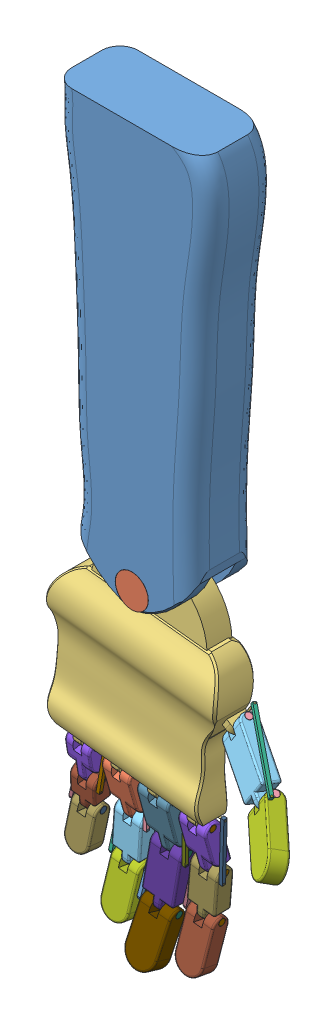
SolidWorks assembly Hand, configuration Default. Lengths in mm.
Overall size (1770.06 4643.82 693.31).
40 component instances, 31 part files, 90 mates.
Components (placement in the parent):
- arm2-2: arm2 [Default] at (66.057 -996.4106 3559.1648) x (-1 0 0) z (0 1 0) size (1268.57 632.71 2564.87)
- armpin2-1: armpin2 [Default] at (66.057 -1176.4106 3359.1648) size (200 200 400)
- palm2-1: palm2 [Default] at (-49.7867 -1857.8333 3453.0614) x (-0.994014 0.109254 0) z (0.109254 0.994014 0) size (1069.09 253.19 1333.97)
- Whitepinthumb2-1: Whitepinthumb2 [Default] at (444.8112 -1862.5283 3540.0476) x (0.743563 -0.485544 -0.45974) z (0.546751 0.837295 0) size (40 40 200)
- bottomthumb2-1: bottomthumb2 [Default] at (602.4673 -1846.045 3639.4098) x (-0.546751 -0.837295 0) z (-0.293211 0.191466 0.936679) size (202.17 424 100.1)
- llink2palmThumb-1: llink2palmThumb [Default] at (692.7586 -1782.9453 3602.1353) x (0.417114 -0.272374 -0.867081) z (0.726003 -0.474077 0.498168) size (20 20 462)
- topThumb2-1: topThumb2 [Default] at (853.3079 -2009.6042 3786.5629) x (-0.546751 -0.837295 0) z (-0.500891 0.32708 0.801328) size (223.09 400 100.1)
- Whitepinthumb2-2: Whitepinthumb2 [Default] at (849.1589 -1887.4628 3671.7184) x (0.743563 -0.485544 0.45974) z (-0.546751 -0.837295 0) size (40 40 200)
- bottomIndex2-1: bottomIndex2 [Default] at (237.9873 -2518.7706 3544.9319) x (-0.994014 0.109254 0) z (-0.036869 -0.335441 0.941339) size (192.89 374 100.1)
- WhitepinIndex-1: WhitepinIndex [Default] at (337.1775 -2394.3221 3540.0476) x (0.00717 0.065231 0.997844) z (-0.994014 0.109254 0) size (40 40 170)
- link1palm-1: link1palm [Default] at (342.7622 -2546.7081 3474.8213) x (0.009115 0.082932 -0.996514) z (0.108873 0.990548 0.083431) size (20 20 387)
- topIndex2-1: topIndex2 [Default] at (179.7632 -3052.1677 3490.7878) x (-0.994014 0.109254 0) z (0.021291 0.193713 0.980827) size (193.09 335 100.1)
- upIndex2-1: upIndex2 [Default] at (208.2828 -2790.8593 3477.1977) x (-0.994014 0.109254 0) z (-0.003078 -0.028007 0.999603) size (193.09 324 100.1)
- WhitepinIndex-2: WhitepinIndex [Default] at (303.8489 -2699.3835 3430.0351) x (0.005058 0.046018 0.998928) z (-0.994014 0.109254 0) size (40 40 170)
- WhitepinIndex-3: WhitepinIndex [Default] at (273.9057 -2973.6443 3422.2586) x (0.012952 0.117841 0.992948) z (-0.994014 0.109254 0) size (40 40 170)
- link2-1: link2 [Default] at (101.6614 -2964.6124 3449.7024) x (0.049922 0.454198 -0.889501) z (0.097181 0.884176 0.456933) size (202.48 20 293.97)
- bottomMiddle2-1: bottomMiddle2 [Default] at (-3.1499 -2515.9675 3537.8989) x (-0.994014 0.109254 0) z (-0.035954 -0.327121 0.944298) size (202.89 424 100.1)
- Whitepinmiddle2-1: Whitepinmiddle2 [Default] at (108.5543 -2369.1937 3540.0476) x (0.054133 0.492512 0.86862) z (-0.994014 0.109254 0) size (40 40 190)
- llinkMiddle-1: llinkMiddle [Default] at (111.2099 -2548.2299 3469.536) x (0.010688 0.097237 -0.995204) z (0.10873 0.989246 0.097823) size (20 20 434)
- upMiddle2-1: upMiddle2 [Default] at (-37.6689 -2831.8595 3475.7117) x (-0.994014 0.109254 0) z (0.008345 0.075929 0.997078) size (213.09 374 100.1)
- topMiddle2-1: topMiddle2 [Default] at (-68.5218 -3114.3963 3519.33) x (-0.994014 0.109254 0) z (0.033324 0.303187 0.952348) size (213.09 345 100.1)
- Whitepinmiddle2-2: Whitepinmiddle2 [Default] at (34.6481 -3045.27 3441.2114) x (0.051008 0.464078 0.884324) z (-0.994014 0.109254 0) size (40 40 190)
- Whitepinmiddle2-3: Whitepinmiddle2 [Default] at (69.962 -2722.1463 3416.3095) x (0.05381 0.489577 0.870298) z (-0.994014 0.109254 0) size (40 40 190)
- linkmid2-1: linkmid2 [Default] at (-115.8972 -2657.5866 3399.8278) x (-0.042435 -0.386079 0.921489) z (-0.100676 -0.915973 -0.388404) size (236.96 20 342.7)
- bottomRing2-1: bottomRing2 [Default] at (-222.8909 -2468.1442 3544.0434) x (-0.994014 0.109254 0) z (-0.037547 -0.341612 0.939091) size (192.89 374 100.1)
- WhitepinRing-1: WhitepinRing [Default] at (-123.6974 -2343.6665 3540.0476) x (0.017517 0.159372 0.987063) z (-0.994014 0.109254 0) size (40 40 170)
- llink2palmRing-1: llink2palmRing [Default] at (-118.2995 -2495.9208 3473.5529) x (0.009875 0.089841 -0.995907) z (0.108807 0.989946 0.090382) size (20 20 387)
- upRing2-1: upRing2 [Default] at (-252.6012 -2740.2855 3473.3803) x (-0.994014 0.109254 0) z (-0.005002 -0.045511 0.998951) size (193.09 324 100.1)
- WhitepinRing-2: WhitepinRing [Default] at (-156.9459 -2647.9993 3428.0113) x (0.04458 0.405596 0.912965) z (-0.994014 0.109254 0) size (40 40 170)
- WhitepinRing-3: WhitepinRing [Default] at (-187.2671 -2922.0376 3415.3746) x (0.042318 0.38502 0.921938) z (-0.994014 0.109254 0) size (40 40 170)
- linkRing2-1: linkRing2 [Default] at (-323.2952 -2585.3326 3412.2107) x (-0.051499 -0.468548 0.881936) z (-0.096355 -0.876656 -0.47137) size (202.48 20 293.97)
- topRing2-1: topRing2 [Default] at (-281.5753 -3002.068 3481.9035) x (-0.994014 0.109254 0) z (0.01888 0.171778 0.984955) size (193.09 335 100.1)
- bottomlittle2-1: bottomlittle2 [Default] at (-446.0836 -2393.6088 3570.4269) x (-0.994014 0.109254 0) z (-0.02642 -0.240374 0.970321) size (172.89 274 100.1)
- linklittle-1: linklittle [Default] at (-372.4692 -2428.6302 3500.2685) x (-0.007809 -0.071048 -0.997442) z (-0.108974 -0.991472 0.071475) size (20 20 298)
- Whitepinlittle2-1: Whitepinlittle2 [Default] at (-386.4181 -2535.4036 3485.3958) x (-0.080786 -0.735011 0.673225) z (-0.994014 0.109254 0) size (40 40 150)
- Whitepinlittle2-2: Whitepinlittle2 [Default] at (-362.2608 -2317.4457 3540.0476) x (-0.101503 -0.923497 0.369933) z (-0.994014 0.109254 0) size (40 40 150)
- uplittle2-1: uplittle2 [Default] at (-467.2053 -2583.9477 3527.1317) x (-0.994014 0.109254 0) z (-0.016764 -0.152521 0.988158) size (173.09 224 100.1)
- toplittle2-1: toplittle2 [Default] at (-487.6102 -2767.7651 3517.4326) x (-0.994014 0.109254 0) z (0.013751 0.12511 0.992048) size (173.09 275 100.1)
- linklittle2-1: linklittle2 [Default] at (-532.5016 -2476.907 3464.9918) x (-0.051863 -0.471861 0.880146) z (-0.096159 -0.874877 -0.474703) size (144.28 20 209.86)
- Whitepinlittle2-3: Whitepinlittle2 [Default] at (-405.6178 -2708.2564 3458.3905) x (-0.080781 -0.734964 0.673278) z (-0.994014 0.109254 0) size (40 40 150)
Mates (geometry in assembly coordinates):
- Concentric1: concentric: cylinder of arm2-2 through (66.057 -1176.4106 3359.1648) axis (0 0 1) radius 100; cylinder of armpin2-1 through (66.057 -1176.4106 3759.1648) axis (0 0 -1) radius 100
- Coincident1: coincident: plane of arm2-2 through (66.057 -996.4106 3759.1648) normal (0 0 1); plane of armpin2-1 through (66.057 -1176.4106 3759.1648) normal (0 0 1)
- Concentric2: concentric: cylinder of armpin2-1 through (66.057 -1176.4106 3759.1648) axis (0 0 -1) radius 100; cylinder of palm2-1 through (66.057 -1176.4106 3445.0448) axis (0 0 1) radius 100
- Coincident3: coincident: plane of arm2-2 through (416.057 -996.4106 3634.6648) normal (0 0 -1); plane of palm2-1 through (428.1649 -1085.4276 3634.6648) normal (0 0 1)
- Concentric3: concentric: cylinder of palm2-1 through (472.6955 -1819.8263 3540.0476) axis (0.546751 0.837295 0) radius 20; cylinder of Whitepinthumb2-1 through (554.1614 -1695.0693 3540.0476) axis (-0.546751 -0.837295 0) radius 20
- Concentric4: concentric: cylinder of Whitepinthumb2-1 through (554.1614 -1695.0693 3540.0476) axis (-0.546751 -0.837295 0) radius 20; cylinder of bottomthumb2-1 through (444.8112 -1862.5283 3540.0476) axis (0.546751 0.837295 0) radius 20
- Coincident4: coincident: plane of palm2-1; plane of bottomthumb2-1
- Coincident5: coincident: plane of Whitepinthumb2-1 through (554.1614 -1695.0693 3540.0476) normal (0.546751 0.837295 0); plane of bottomthumb2-1 through (823.712 -1871.0849 3607.0248) normal (0.546751 0.837295 0)
- Concentric5: concentric: cylinder of bottomthumb2-1 through (849.6436 -1886.7206 3671.7184) axis (-0.546751 -0.837295 0) radius 20; cylinder of Whitepinthumb2-2 through (739.8087 -2054.9218 3671.7184) axis (0.546751 0.837295 0) radius 20
- Concentric6: concentric: cylinder of topThumb2-1 through (739.8087 -2054.9218 3671.7184) axis (0.546751 0.837295 0) radius 20; cylinder of Whitepinthumb2-2 through (739.8087 -2054.9218 3671.7184) axis (0.546751 0.837295 0) radius 20
- Coincident6: coincident: plane of bottomthumb2-1 through (755.4775 -1975.5793 3607.0248) normal (-0.546751 -0.837295 0); plane of topThumb2-1 through (772.3122 -1986.5723 3601.7407) normal (0.546751 0.837295 0)
- Coincident7: coincident: plane of topThumb2-1 through (1058.7143 -2024.3017 3796.1637) normal (0.546751 0.837295 0); plane of Whitepinthumb2-2 through (849.1589 -1887.4628 3671.7184) normal (0.546751 0.837295 0)
- Concentric7: concentric: cylinder of llink2palmThumb-1 through (855.3542 -1889.1196 3713.705) axis (0.546751 0.837295 0) radius 5.75; cylinder of topThumb2-1 through (866.2892 -1872.3737 3713.705) axis (-0.546751 -0.837295 0) radius 5.75
- Concentric8: concentric: cylinder of palm2-1 through (539.1402 -1661.3741 3490.0476) axis (-0.546751 -0.837295 0) radius 5.75; cylinder of llink2palmThumb-1 through (529.4081 -1676.2779 3490.0476) axis (0.546751 0.837295 0) radius 5.75
- Coincident8: coincident: plane of llink2palmThumb-1 through (703.6936 -1766.1994 3602.1353) normal (0.546751 0.837295 0); plane of topThumb2-1 through (866.2892 -1872.3737 3713.705) normal (0.546751 0.837295 0)
- Concentric9: concentric: cylinder of palm2-1 through (478.9859 -2409.9085 3540.0476) axis (-0.994014 0.109254 0) radius 20; cylinder of WhitepinIndex-1 through (168.1952 -2375.7489 3540.0476) axis (0.994014 -0.109254 0) radius 20
- Concentric10: concentric: cylinder of bottomIndex2-1 through (168.1952 -2375.7489 3540.0476) axis (0.994014 -0.109254 0) radius 20; cylinder of WhitepinIndex-1 through (168.1952 -2375.7489 3540.0476) axis (0.994014 -0.109254 0) radius 20
- Coincident9: coincident: plane of palm2-1; plane of bottomIndex2-1
- Coincident10: coincident: plane of WhitepinIndex-1 through (337.1775 -2394.3221 3540.0476) normal (0.994014 -0.109254 0); plane of bottomIndex2-1 through (310.7387 -2634.8687 3400.1787) normal (0.994014 -0.109254 0)
- Concentric11: concentric: cylinder of bottomIndex2-1 through (303.6501 -2699.3617 3430.0351) axis (-0.994014 0.109254 0) radius 20; cylinder of WhitepinIndex-2 through (134.8666 -2680.8104 3430.0351) axis (0.994014 -0.109254 0) radius 20
- Concentric12: concentric: cylinder of upIndex2-1 through (134.8666 -2680.8104 3430.0351) axis (0.994014 -0.109254 0) radius 20; cylinder of WhitepinIndex-2 through (134.8666 -2680.8104 3430.0351) axis (0.994014 -0.109254 0) radius 20
- Coincident11: coincident: plane of bottomIndex2-1 through (201.5959 -2622.8727 3400.1787) normal (-0.994014 0.109254 0); plane of upIndex2-1 through (200.1218 -2636.2843 3381.4638) normal (0.994014 -0.109254 0)
- Coincident12: coincident: plane of upIndex2-1 through (279.4305 -2921.5475 3373.7154) normal (0.994014 -0.109254 0); plane of WhitepinIndex-2 through (303.8489 -2699.3835 3430.0351) normal (0.994014 -0.109254 0)
- Concentric13: concentric: cylinder of upIndex2-1 through (274.7868 -2973.7412 3422.2586) axis (-0.994014 0.109254 0) radius 20; cylinder of WhitepinIndex-3 through (104.9233 -2955.0712 3422.2586) axis (0.994014 -0.109254 0) radius 20
- Concentric15: concentric: cylinder of topIndex2-1 through (104.9233 -2955.0712 3422.2586) axis (0.994014 -0.109254 0) radius 20; cylinder of WhitepinIndex-3 through (104.9233 -2955.0712 3422.2586) axis (0.994014 -0.109254 0) radius 20
- Coincident13: coincident: plane of topIndex2-1 through (168.8576 -2922.5642 3363.4732) normal (0.994014 -0.109254 0); plane of upIndex2-1 through (170.2878 -2909.5515 3373.7154) normal (-0.994014 0.109254 0)
- Coincident14: coincident: plane of topIndex2-1 through (248.7304 -3202.695 3417.065) normal (0.994014 -0.109254 0); plane of WhitepinIndex-3 through (273.9057 -2973.6443 3422.2586) normal (0.994014 -0.109254 0)
- Concentric16: concentric: cylinder of palm2-1 through (362.4327 -2365.9112 3490.0476) axis (-0.994014 0.109254 0) radius 5.75; cylinder of link1palm-1 through (362.6315 -2365.9331 3490.0476) axis (-0.994014 0.109254 0) radius 5.75
- Concentric21: concentric: cylinder of link1palm-1 through (322.3486 -2732.4359 3459.178) axis (-0.994014 0.109254 0) radius 5.75; cylinder of upIndex2-1 through (322.3486 -2732.4359 3459.178) axis (-0.994014 0.109254 0) radius 5.75
- Coincident15: coincident: plane of link1palm-1 through (342.7622 -2546.7081 3474.8213) normal (0.994014 -0.109254 0); plane of upIndex2-1 through (322.3486 -2732.4359 3459.178) normal (0.994014 -0.109254 0)
- Concentric22: concentric: cylinder of topIndex2-1 through (81.9799 -2962.4491 3449.7024) axis (0.994014 -0.109254 0) radius 5.75; cylinder of link2-1 through (101.6614 -2964.6124 3449.7024) axis (-0.994014 0.109254 0) radius 5.75
- Concentric23: concentric: cylinder of bottomIndex2-1 through (117.8068 -2634.6582 3413.9436) axis (0.994014 -0.109254 0) radius 5.75; cylinder of link2-1 through (137.687 -2636.8433 3413.9436) axis (-0.994014 0.109254 0) radius 5.75
- Coincident16: coincident: plane of bottomIndex2-1 through (117.8068 -2634.6582 3413.9436) normal (-0.994014 0.109254 0); plane of link2-1 through (81.7811 -2962.4273 3449.7024) normal (-0.994014 0.109254 0)
- Concentric24: concentric: cylinder of palm2-1 through (478.9859 -2409.9085 3540.0476) axis (-0.994014 0.109254 0) radius 20; cylinder of Whitepinmiddle2-1 through (-80.3083 -2348.4355 3540.0476) axis (0.994014 -0.109254 0) radius 20
- Concentric25: concentric: cylinder of bottomMiddle2-1 through (-80.3083 -2348.4355 3540.0476) axis (0.994014 -0.109254 0) radius 20; cylinder of Whitepinmiddle2-1 through (-80.3083 -2348.4355 3540.0476) axis (0.994014 -0.109254 0) radius 20
- Coincident17: coincident: plane of palm2-1; plane of bottomMiddle2-1
- Coincident18: coincident: plane of bottomMiddle2-1 through (-112.0402 -2637.1393 3385.8782) normal (-0.994014 0.109254 0); plane of Whitepinmiddle2-1 through (-80.3083 -2348.4355 3540.0476) normal (-0.994014 0.109254 0)
- Concentric26: concentric: cylinder of palm2-1 through (131.8215 -2340.5644 3490.0476) axis (-0.994014 0.109254 0) radius 5.75; cylinder of llinkMiddle-1 through (134.0083 -2340.8047 3490.0476) axis (-0.994014 0.109254 0) radius 5.75
- Concentric27: concentric: cylinder of bottomMiddle2-1 through (70.8431 -2722.2432 3416.3095) axis (-0.994014 0.109254 0) radius 20; cylinder of Whitepinmiddle2-3 through (-118.9007 -2701.3881 3416.3095) axis (0.994014 -0.109254 0) radius 20
- Concentric28: concentric: cylinder of upMiddle2-1 through (-118.9007 -2701.3881 3416.3095) axis (0.994014 -0.109254 0) radius 20; cylinder of Whitepinmiddle2-3 through (-118.9007 -2701.3881 3416.3095) axis (0.994014 -0.109254 0) radius 20
- Coincident19: coincident: plane of bottomMiddle2-1 through (-42.2604 -2644.8089 3385.8782) normal (-0.994014 0.109254 0); plane of upMiddle2-1 through (-44.2903 -2663.2769 3362.6363) normal (0.994014 -0.109254 0)
- Coincident20: coincident: plane of upMiddle2-1 through (39.5877 -2998.498 3387.4618) normal (0.994014 -0.109254 0); plane of Whitepinmiddle2-3 through (69.962 -2722.1463 3416.3095) normal (0.994014 -0.109254 0)
- Concentric29: concentric: cylinder of llinkMiddle-1 through (88.2679 -2756.9609 3448.8954) axis (-0.994014 0.109254 0) radius 5.75; cylinder of upMiddle2-1 through (88.2679 -2756.9609 3448.8954) axis (-0.994014 0.109254 0) radius 5.75
- Coincident21: coincident: plane of llinkMiddle-1 through (111.2099 -2548.2299 3469.536) normal (0.994014 -0.109254 0); plane of upMiddle2-1 through (88.2679 -2756.9609 3448.8954) normal (0.994014 -0.109254 0)
- Concentric30: concentric: cylinder of upMiddle2-1 through (35.5292 -3045.3668 3441.2114) axis (-0.994014 0.109254 0) radius 20; cylinder of Whitepinmiddle2-2 through (-154.2145 -3024.5118 3441.2114) axis (0.994014 -0.109254 0) radius 20
- Concentric31: concentric: cylinder of topMiddle2-1 through (-154.2145 -3024.5118 3441.2114) axis (0.994014 -0.109254 0) radius 20; cylinder of Whitepinmiddle2-2 through (-154.2145 -3024.5118 3441.2114) axis (0.994014 -0.109254 0) radius 20
- Coincident22: coincident: plane of upMiddle2-1 through (-79.4952 -2985.4094 3387.4618) normal (-0.994014 0.109254 0); plane of topMiddle2-1 through (-81.0974 -2999.9865 3378.3433) normal (0.994014 -0.109254 0)
- Coincident23: coincident: plane of topMiddle2-1 through (9.5712 -3273.425 3462.2218) normal (0.994014 -0.109254 0); plane of Whitepinmiddle2-2 through (34.6481 -3045.27 3441.2114) normal (0.994014 -0.109254 0)
- Concentric32: concentric: cylinder of topMiddle2-1 through (-176.8105 -3028.7282 3469.5953) axis (0.994014 -0.109254 0) radius 6.5; cylinder of linkmid2-1 through (-156.9302 -3030.9133 3469.5953) axis (-0.994014 0.109254 0) radius 5.75
- Concentric33: concentric: cylinder of bottomMiddle2-1 through (-126.0362 -2656.4722 3399.8278) axis (0.994014 -0.109254 0) radius 5.75; cylinder of linkmid2-1 through (-115.8972 -2657.5866 3399.8278) axis (-0.994014 0.109254 0) radius 5.75
- Concentric34: concentric: cylinder of palm2-1 through (478.9859 -2409.9085 3540.0476) axis (-0.994014 0.109254 0) radius 20; cylinder of WhitepinRing-1 through (-292.6798 -2325.0934 3540.0476) axis (0.994014 -0.109254 0) radius 20
- Concentric35: concentric: cylinder of bottomRing2-1 through (-292.6798 -2325.0934 3540.0476) axis (0.994014 -0.109254 0) radius 20; cylinder of WhitepinRing-1 through (-292.6798 -2325.0934 3540.0476) axis (0.994014 -0.109254 0) radius 20
- Coincident25: coincident: plane of palm2-1; plane of bottomRing2-1
- Coincident26: coincident: plane of bottomRing2-1 through (-319.0172 -2564.7168 3398.5839) normal (-0.994014 0.109254 0); plane of WhitepinRing-1 through (-292.6798 -2325.0934 3540.0476) normal (-0.994014 0.109254 0)
- Concentric36: concentric: cylinder of palm2-1 through (-98.4423 -2315.2557 3490.0476) axis (-0.994014 0.109254 0) radius 5.75; cylinder of llink2palmRing-1 through (-98.4423 -2315.2557 3490.0476) axis (-0.994014 0.109254 0) radius 5.75
- Coincident27: coincident: plane of palm2-1; plane of llink2palmRing-1
- Concentric37: concentric: cylinder of bottomRing2-1 through (-157.1448 -2647.9775 3428.0113) axis (-0.994014 0.109254 0) radius 20; cylinder of WhitepinRing-2 through (-325.9283 -2629.4262 3428.0113) axis (0.994014 -0.109254 0) radius 20
- Concentric38: concentric: cylinder of upRing2-1 through (-325.9283 -2629.4262 3428.0113) axis (0.994014 -0.109254 0) radius 20; cylinder of WhitepinRing-2 through (-325.9283 -2629.4262 3428.0113) axis (0.994014 -0.109254 0) radius 20
- Coincident28: coincident: plane of bottomRing2-1 through (-259.1776 -2571.2939 3398.5839) normal (-0.994014 0.109254 0); plane of upRing2-1 through (-260.5804 -2584.0573 3380.353) normal (0.994014 -0.109254 0)
- Coincident29: coincident: plane of upRing2-1 through (-350.2345 -2850.5692 3367.762) normal (-0.994014 0.109254 0); plane of WhitepinRing-2 through (-325.9283 -2629.4262 3428.0113) normal (-0.994014 0.109254 0)
- Concentric39: concentric: cylinder of upRing2-1 through (-185.9884 -2922.1782 3415.3746) axis (-0.994014 0.109254 0) radius 20; cylinder of WhitepinRing-3 through (-356.2495 -2903.4645 3415.3746) axis (0.994014 -0.109254 0) radius 20
- Concentric40: concentric: cylinder of WhitepinRing-3 through (-356.2495 -2903.4645 3415.3746) axis (0.994014 -0.109254 0) radius 20; cylinder of topRing2-1 through (-356.2495 -2903.4645 3415.3746) axis (0.994014 -0.109254 0) radius 20
- Coincident30: coincident: plane of upRing2-1 through (-241.0918 -2862.5653 3367.762) normal (0.994014 -0.109254 0); plane of topRing2-1 through (-242.4715 -2875.1184 3357.4862) normal (-0.994014 0.109254 0)
- Coincident31: coincident: plane of WhitepinRing-3 through (-187.2671 -2922.0376 3415.3746) normal (0.994014 -0.109254 0); plane of topRing2-1 through (-212.4234 -3150.9147 3405.0096) normal (0.994014 -0.109254 0)
- Concentric43: concentric: cylinder of llink2palmRing-1 through (-138.7007 -2681.5356 3456.6063) axis (-0.994014 0.109254 0) radius 5.75; cylinder of upRing2-1 through (-138.5019 -2681.5574 3456.6063) axis (-0.994014 0.109254 0) radius 5.75
- Concentric46: concentric: cylinder of palm2-1 through (478.9859 -2409.9085 3540.0476) axis (-0.994014 0.109254 0) radius 20; cylinder of Whitepinlittle2-2 through (-511.3629 -2301.0576 3540.0476) axis (0.994014 -0.109254 0) radius 20
- Concentric47: concentric: cylinder of bottomlittle2-1 through (-511.3629 -2301.0576 3540.0476) axis (0.994014 -0.109254 0) radius 20; cylinder of Whitepinlittle2-2 through (-511.3629 -2301.0576 3540.0476) axis (0.994014 -0.109254 0) radius 20
- Coincident33: coincident: plane of palm2-1; plane of bottomlittle2-1
- Coincident34: coincident: plane of bottomlittle2-1 through (-528.5938 -2457.8285 3449.2127) normal (-0.994014 0.109254 0); plane of Whitepinlittle2-2 through (-511.3629 -2301.0576 3540.0476) normal (-0.994014 0.109254 0)
- Concentric48: concentric: cylinder of bottomlittle2-1 through (-385.1394 -2535.5441 3485.3958) axis (-0.994014 0.109254 0) radius 20; cylinder of Whitepinlittle2-1 through (-535.5202 -2519.0155 3485.3958) axis (0.994014 -0.109254 0) radius 20
- Concentric49: concentric: cylinder of Whitepinlittle2-1 through (-535.5202 -2519.0155 3485.3958) axis (0.994014 -0.109254 0) radius 20; cylinder of uplittle2-1 through (-535.5202 -2519.0155 3485.3958) axis (0.994014 -0.109254 0) radius 20
- Coincident35: coincident: plane of bottomlittle2-1 through (-429.3912 -2468.732 3449.2127) normal (0.994014 -0.109254 0); plane of uplittle2-1 through (-429.8826 -2473.2027 3443.6599) normal (-0.994014 0.109254 0)
- Coincident36: coincident: plane of Whitepinlittle2-1 through (-386.4181 -2535.4036 3485.3958) normal (0.994014 -0.109254 0); plane of uplittle2-1 through (-399.0749 -2650.5579 3416.808) normal (0.994014 -0.109254 0)
- Concentric50: concentric: cylinder of linklittle-1 through (-387.973 -2569.6868 3510.4373) axis (0.994014 -0.109254 0) radius 5.75; cylinder of uplittle2-1 through (-368.2915 -2571.8501 3510.4373) axis (-0.994014 0.109254 0) radius 5.75
- Concentric51: concentric: cylinder of palm2-1 through (-337.0056 -2289.0348 3490.0476) axis (-0.994014 0.109254 0) radius 5.75; cylinder of linklittle-1 through (-356.8859 -2286.8497 3490.0476) axis (0.994014 -0.109254 0) radius 5.75
- Coincident37: coincident: plane of palm2-1; plane of linklittle-1
- Concentric52: concentric: cylinder of uplittle2-1 through (-404.3391 -2708.397 3458.3905) axis (-0.994014 0.109254 0) radius 20; cylinder of Whitepinlittle2-3 through (-554.7199 -2691.8684 3458.3905) axis (0.994014 -0.109254 0) radius 20
- Concentric53: concentric: cylinder of toplittle2-1 through (-554.7199 -2691.8684 3458.3905) axis (0.994014 -0.109254 0) radius 20; cylinder of Whitepinlittle2-3 through (-554.7199 -2691.8684 3458.3905) axis (0.994014 -0.109254 0) radius 20
- Coincident38: coincident: plane of toplittle2-1 through (-574.3748 -2870.693 3430.8141) normal (-0.994014 0.109254 0); plane of Whitepinlittle2-3 through (-554.7199 -2691.8684 3458.3905) normal (-0.994014 0.109254 0)
- Coincident39: coincident: plane of uplittle2-1 through (-448.9744 -2645.0733 3416.808) normal (0.994014 -0.109254 0); plane of toplittle2-1 through (-450.5868 -2659.7438 3402.4949) normal (-0.994014 0.109254 0)
- Concentric55: concentric: cylinder of toplittle2-1 through (-577.8702 -2701.1287 3485.0796) axis (0.994014 -0.109254 0) radius 5.75; cylinder of linklittle2-1 through (-557.3935 -2703.3793 3485.0796) axis (-0.994014 0.109254 0) radius 5.75
- Concentric56: concentric: cylinder of bottomlittle2-1 through (-552.3819 -2474.722 3464.9918) axis (0.994014 -0.109254 0) radius 5.75; cylinder of linklittle2-1 through (-532.5016 -2476.907 3464.9918) axis (-0.994014 0.109254 0) radius 5.75
- Coincident40: coincident: plane of bottomlittle2-1 through (-552.3819 -2474.722 3464.9918) normal (-0.994014 0.109254 0); plane of linklittle2-1 through (-552.3819 -2474.722 3464.9918) normal (-0.994014 0.109254 0)
- Coincident41: coincident: plane of topMiddle2-1 through (-176.8105 -3028.7282 3469.5953) normal (-0.994014 0.109254 0); plane of linkmid2-1 through (-135.7775 -2655.4016 3399.8278) normal (-0.994014 0.109254 0)
- Concentric57: concentric: cylinder of linkRing2-1 through (-359.3797 -2913.6374 3442.5906) axis (-0.994014 0.109254 0) radius 5.75; cylinder of topRing2-1 through (-379.26 -2911.4523 3442.5906) axis (0.994014 -0.109254 0) radius 5.75
- Concentric58: concentric: cylinder of bottomRing2-1 through (-342.9766 -2583.1694 3412.2107) axis (0.994014 -0.109254 0) radius 5.75; cylinder of linkRing2-1 through (-323.2952 -2585.3326 3412.2107) axis (-0.994014 0.109254 0) radius 5.75
- Coincident42: coincident: plane of linkRing2-1 through (-343.1754 -2583.1475 3412.2107) normal (-0.994014 0.109254 0); plane of topRing2-1 through (-379.26 -2911.4523 3442.5906) normal (-0.994014 0.109254 0)
- Parallel1: parallel: plane of bottomIndex2-1 through (141.7563 -2616.2956 3400.1787) normal (-0.994014 0.109254 0); plane of bottomMiddle2-1 through (-112.0402 -2637.1393 3385.8782) normal (-0.994014 0.109254 0)
- Parallel2: parallel: plane of bottomIndex2-1 through (141.7563 -2616.2956 3400.1787) normal (-0.994014 0.109254 0); plane of bottomRing2-1 through (-319.0172 -2564.7168 3398.5839) normal (-0.994014 0.109254 0)
- Parallel3: parallel: plane of bottomIndex2-1 through (141.7563 -2616.2956 3400.1787) normal (-0.994014 0.109254 0); plane of bottomlittle2-1 through (-528.5938 -2457.8285 3449.2127) normal (-0.994014 0.109254 0)
